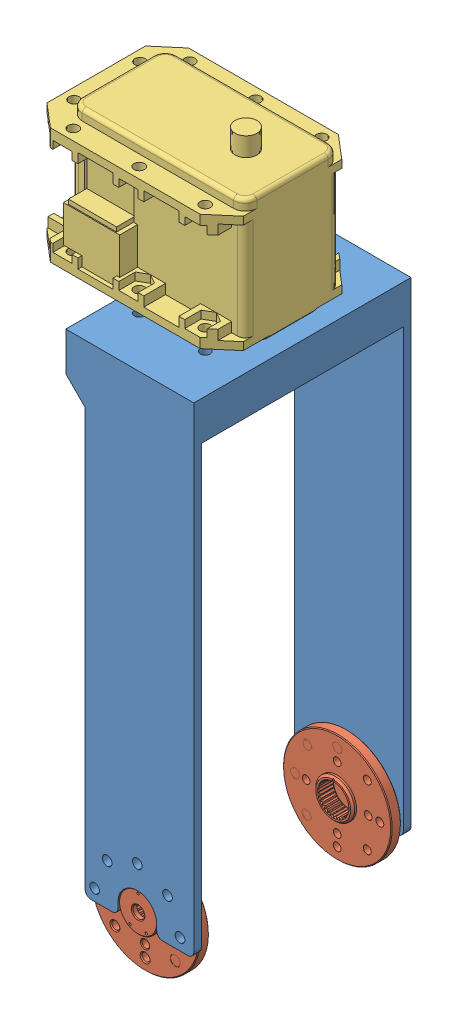
SolidWorks assembly Link5, configuration Default. Lengths in mm.
Overall size (53.15 175.45 56).
4 component instances, 3 part files, 9 mates.
Components (placement in the parent):
- myFR08-H101-1: myFR08-H101 [Default] at (10.4465 -9.2317 144.2351) size (33 124.1 56)
- HN05-N101-1: HN05-N101 [Default] at (23.8965 -6.2317 139.7351) x (1 0 0) z (0 -1 0) size (28 5.3 28)
- HN05-N101-2: HN05-N101 [Default] at (23.8965 -6.2317 92.7351) x (-1 0 0) z (0 -1 0) size (28 5.3 28)
- MX-28T_R-1: MX-28T_R [Default] at (23.8965 132.6183 116.2351) x (0 0 1) z (0 1 0) size (35.6 50.71 41.85)
Mates (geometry in assembly coordinates):
- Concentric1: concentric: circle of myFR08-H101-1; circle of MX-28T_R-1
- Concentric2: concentric: circle of myFR08-H101-1; circle of MX-28T_R-1
- Coincident1: coincident anti-aligned: plane of myFR08-H101-1 through (10.4465 114.8683 142.2351) normal (0 1 0); plane of MX-28T_R-1 through (23.8965 114.8683 116.2351) normal (0 -1 0)
- Concentric3: concentric: circle of myFR08-H101-1; circle of HN05-N101-1
- Concentric4: concentric: circle of myFR08-H101-1; circle of HN05-N101-1
- Coincident2: coincident anti-aligned: plane of myFR08-H101-1 through (10.4465 -9.2317 142.2351) normal (0 0 -1); plane of HN05-N101-1 through (23.8965 -6.2317 142.2351) normal (0 0 1)
- Concentric5: concentric: circle of myFR08-H101-1; circle of HN05-N101-2
- Concentric6: concentric: circle of myFR08-H101-1; circle of HN05-N101-2
- Coincident3: coincident anti-aligned: plane of myFR08-H101-1 through (10.4465 -9.2317 90.2351) normal (0 0 1); plane of HN05-N101-2 through (23.8965 -6.2317 90.2351) normal (0 0 -1)
